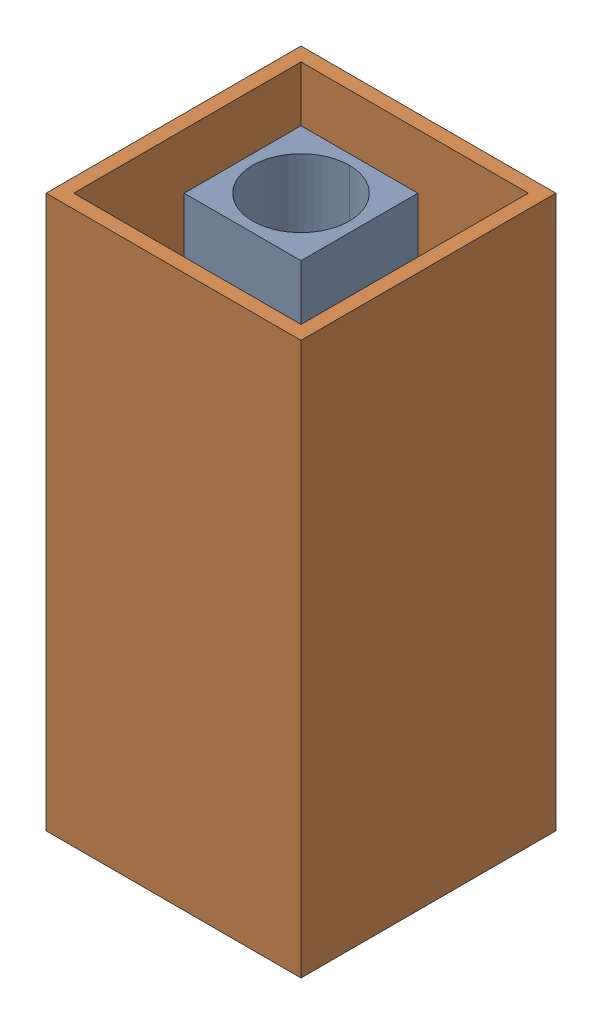
SolidWorks assembly piezo-drive-subassembly-1, configuration Default. Lengths in mm.
Overall size (2.77 6 2.77).
3 component instances, 2 part files, 0 mates.
Components (placement in the parent):
- 6701982208-1: 6701982208 [Default] at (27.7 14.8 0) (suppressed, hidden)
- sql-rv-1.8-6-12_nc-1: sql-rv-1.8-6-12_nc [Default] at origin size (1.27 6 1.27)
- sql-rv-1.8-6-12_nc-1-1: sql-rv-1.8-6-12_nc-1 [Default] at origin size (2.77 6 2.77)
